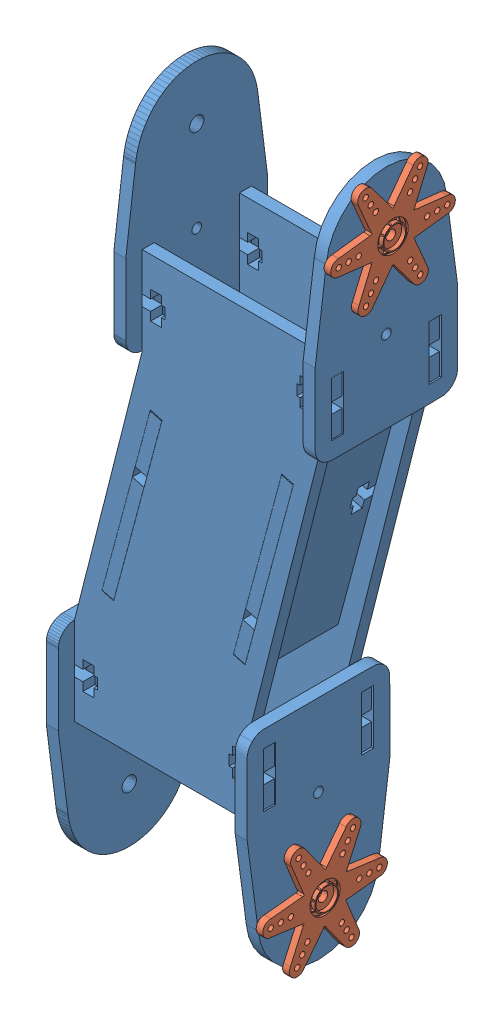
SolidWorks assembly left_thigh, configuration Default. Lengths in mm.
Overall size (81.05 224.87 48.77).
3 component instances, 2 part files, 2 mates.
Components (placement in the parent):
- left_thigh_100-1: left_thigh_100 [Default] at (-70.6339 -75.5014 197.3954) size (78.61 212.34 48.77)
- servo_arm_6_sided-3: servo_arm_6_sided [Default] at (7.6584 77.7083 213.2729) x (0 0.867392 -0.497625) z (0 -0.497625 -0.867392) size (36.45 6.25 32.2)
- servo_arm_6_sided-4: servo_arm_6_sided [Default] at (-12.0999 -99.5867 213.3713) x (0 0.873631 0.48659) z (0 0.48659 -0.873631) size (36.45 6.25 32.2)
Mates (geometry in assembly coordinates):
- ProfileCenter1: profile center aligned: circle of left_thigh_100-1; circle of servo_arm_6_sided-3
- ProfileCenter2: profile center anti-aligned: circle of left_thigh_100-1; circle of servo_arm_6_sided-4
